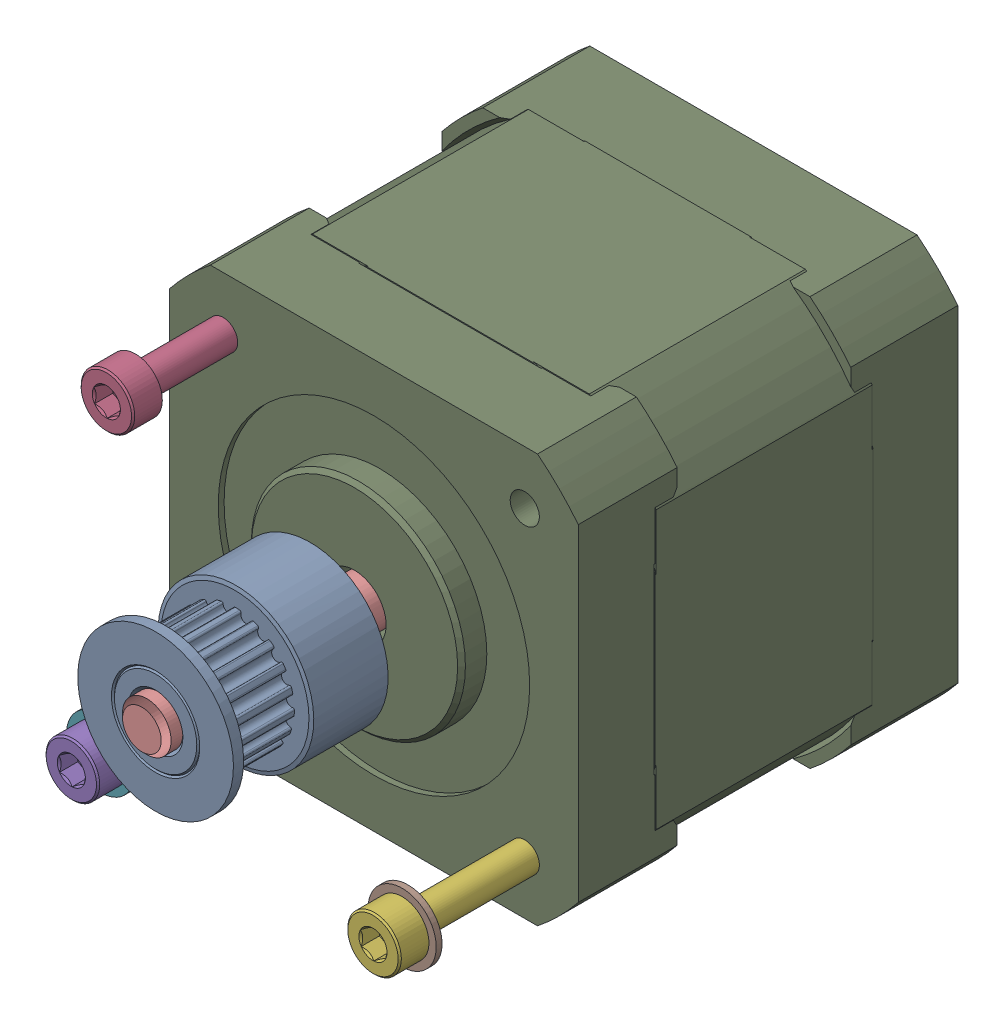
SolidWorks assembly NEMA17 Midsize v1, configuration Varsayılan. Lengths in mm.
Overall size (42.2 42.61 62.85).
12 component instances, 10 part files, 0 mates.
Components (placement in the parent):
- GT2 20T 6mm Powge v2-1: GT2 20T 6mm Powge v2 [Varsayılan] at (0 0 23.1991) x (0 0 1) z (-0.198591 -0.980083 0) size (16 16 16)
- M3x12 SHCS-1: M3x12 SHCS [Varsayılan] at (-15.5 15.5 13.76) x (0.998537 0.054079 0) z (0 0 -1) size (5.5 5.5 15)
- M3x16 SHCS-1: M3x16 SHCS [Varsayılan] at (-15.5 -15.5 17.36) x (0.998537 0.054079 0) z (0 0 -1) size (5.5 5.5 19)
- M3x16 SHCS-2: M3x16 SHCS [Varsayılan] at (15.5 -15.5 17.36) x (0.998537 0.054079 0) z (0 0 -1) size (5.5 5.5 19)
- M3 Washer-1: M3 Washer [Varsayılan] at (-15.5 -15.5 29.36) x (0.998537 0.054079 0) z (0 0 -1) size (7 7 0.6)
- M3 Washer-2: M3 Washer [Varsayılan] at (15.5 -15.5 29.36) x (0.998537 0.054079 0) z (0 0 -1) size (7 7 0.6)
- NEMA17 Midsize v1-3-1: NEMA17 Midsize v1-3 [Varsayılan] at origin size (42.2 42.61 41)
- NEMA17 Midsize v1-4-1: NEMA17 Midsize v1-4 [Varsayılan] at origin size (5.02 5.02 60.35)
- NEMA17 Midsize v1-5-1: NEMA17 Midsize v1-5 [Varsayılan] at origin size (5.33 5.33 23.75)
- NEMA17 Midsize v1-6-1: NEMA17 Midsize v1-6 [Varsayılan] at origin size (5.33 5.33 23.75)
- NEMA17 Midsize v1-7-1: NEMA17 Midsize v1-7 [Varsayılan] at origin size (5.33 5.33 23.75)
- NEMA17 Midsize v1-8-1: NEMA17 Midsize v1-8 [Varsayılan] at origin size (5.33 5.33 23.75)
